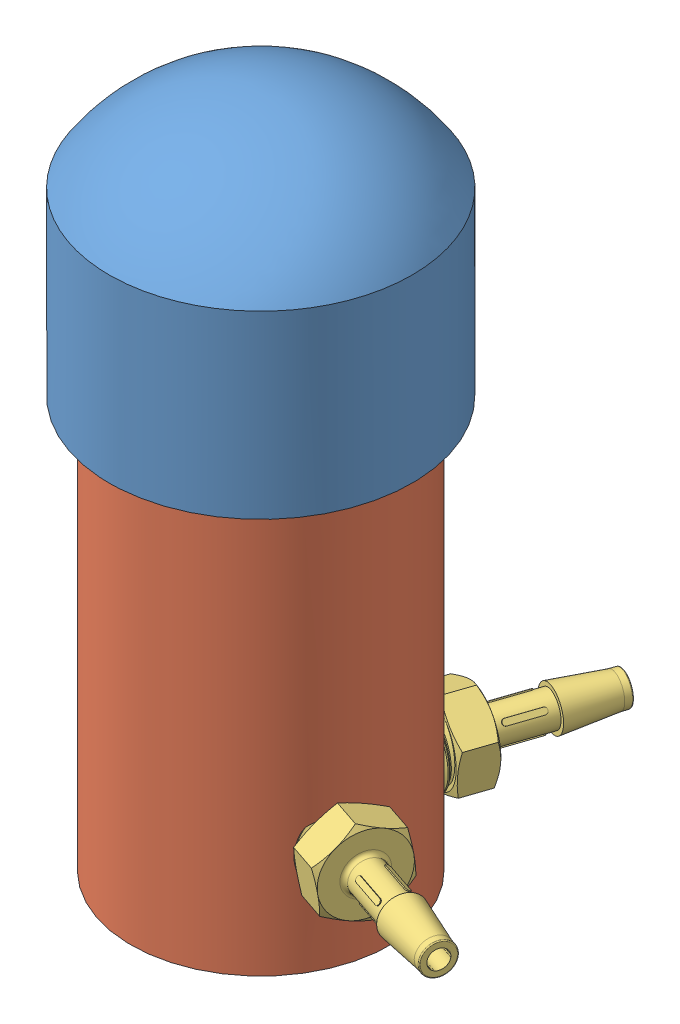
SolidWorks assembly Assem1, configuration Default. Lengths in mm.
Overall size (83.28 125.41 83.87).
4 component instances, 3 part files, 3 mates.
Components (placement in the parent):
- pvc-cap-1: pvc-cap [Default] at origin size (56.41 48.88 56.41)
- pvc-pipe-1: pvc-pipe [Default] at (0 12.3671 0) x (-0.94767 0 -0.319251) z (-0.319251 0 0.94767) size (48.31 88.9 48.31)
- 2808K270_SUPER-FLOW BARBED FITTING FOR FOOD BEVERAGE-1: 2808K270_SUPER-FLOW BARBED FITTING FOR FOOD BEVERAGE [2808K27] at (29.6117 -57.4829 9.9756) x (0.94767 0 0.319251) z (-0.315717 -0.148389 0.937179) size (43.5 16.5 14.36)
- 2808K270_SUPER-FLOW BARBED FITTING FOR FOOD BEVERAGE-2: 2808K270_SUPER-FLOW BARBED FITTING FOR FOOD BEVERAGE [2808K27] at (10.1735 -63.8329 -30.1992) x (0.319251 0 -0.94767) z (0.93737 -0.147035 0.315781) size (43.5 16.5 14.36)
Mates (geometry in assembly coordinates):
- Concentric2: concentric anti-aligned: cylinder of pvc-cap-1 through (0 33.5788 0) axis (0 -1 0) radius 24.1427; cylinder of pvc-pipe-1 through (0 -76.5329 0) axis (0 1 0) radius 24.1554
- Concentric3: concentric aligned: cylinder of pvc-pipe-1 through (31.8216 -57.4829 10.7201) axis (-0.94767 0 -0.319251) radius 4.7625; cylinder of 2808K270_SUPER-FLOW BARBED FITTING FOR FOOD BEVERAGE-1 through (41.3851 -57.4829 13.9418) axis (-0.94767 0 -0.319251) radius 4.4317
- Concentric4: concentric aligned: cylinder of pvc-pipe-1 through (10.7201 -63.8329 -31.8216) axis (-0.319251 0 0.94767) radius 4.7625; cylinder of 2808K270_SUPER-FLOW BARBED FITTING FOR FOOD BEVERAGE-2 through (14.1397 -63.8329 -41.9725) axis (-0.319251 0 0.94767) radius 4.4317
